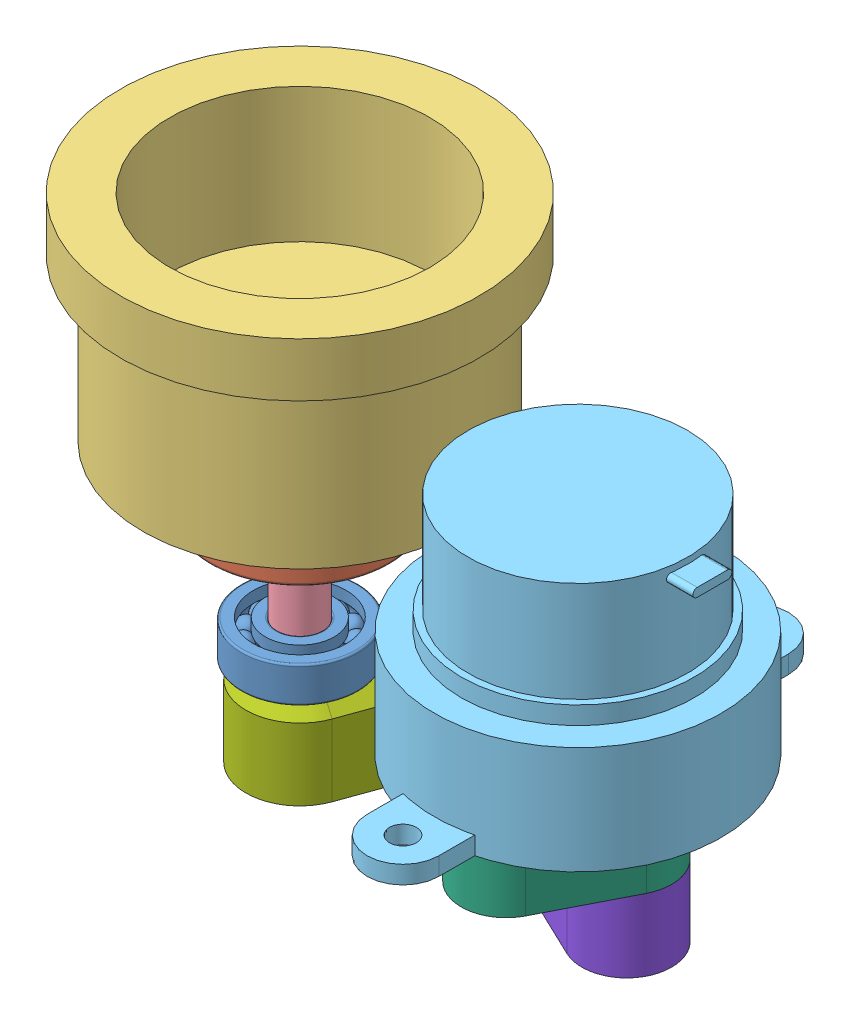
SolidWorks assembly 摇头底座装配体, configuration Default. Lengths in mm.
Overall size (74.74 63 55.47).
14 component instances, 12 part files, 33 mates.
Components (placement in the parent):
- 风扇底座外壳-1: 风扇底座外壳 [默认] at origin size (80 55 60) (hidden)
- Rolling bearings 619-5 GB 276-94-1: Rolling bearings 619-5 GB 276-94 [Rolling bearings 619-5 GB 276-94] at (0 22 0) x (0 1 0) z (-0.041534 0 0.999137) size (4 13 13)
- Rolling bearings 619-9 GB 276-94-1: Rolling bearings 619-9 GB 276-94 [Rolling bearings 619-9 GB 276-94] at (0 37 0) x (0 1 0) z (0.719572 0 0.694418) size (6 20 20)
- 风扇摇头底座-1: 风扇摇头底座 [默认] at (0 34 0) x (0.55495 0 0.831883) z (-0.831883 0 0.55495) size (40 31 40)
- M4轴肩螺丝绘制-1: M4轴肩螺丝绘制 [默认] at (0 8 0) x (0.067555 0 -0.997716) z (0 1 0) size (9 9 41.5)
- 小电动机-1: 小电动机 [默认] at (31 26.2 0) x (-1 0 0) z (0 0 -1) size (32 35.4 47)
- 曲柄-1: 曲柄 [默认] at (23 10 0) x (0.45445 0 -0.890772) z (0.890772 0 0.45445) size (20 10 10)
- 摇杆-1: 摇杆 [默认] at (0 10 0) x (0.339342 0 -0.940663) z (0.940663 0 0.339342) size (32 10 12)
- 连杆-1: 连杆 [默认] at (6.7868 2 -18.8133) x (0.902507 0 0.430676) z (-0.430676 0 0.902507) size (33 8 10)
- M3轴肩螺丝绘制-1: M3轴肩螺丝绘制 [默认] at (27.5445 21.5 -8.9077) x (-0.278627 0 -0.960399) z (0 -1 0) size (7 7 19.5)
- M3轴肩螺丝绘制-2: M3轴肩螺丝绘制 [默认] at (6.7868 21.5 -18.8133) x (-0.865706 0 -0.500553) z (0 -1 0) size (7 7 19.5)
- M3防松螺母-1: M3防松螺母 [默认] at (27.5445 15.5 -8.9077) x (-0.17481 0 0.984602) z (-0.984602 0 -0.17481) size (5.5 3.9 6.29)
- M3防松螺母-2: M3防松螺母 [默认] at (6.7868 15.5 -18.8133) x (0.176453 0 0.984309) z (-0.984309 0 0.176453) size (5.5 3.9 6.29)
- M4防松螺母-1: M4防松螺母 [默认] at (0 15 0) x (0.176453 0 0.984309) z (0.984309 0 -0.176453) size (7 5 8.02)
Mates (geometry in assembly coordinates):
- 同心1: concentric anti-aligned: cylinder of 风扇底座外壳-1 through (0 40 0) axis (0 1 0) radius 6.5; cylinder of Rolling bearings 619-5 GB 276-94-1 through (0 13.2893 0) axis (0 -1 0) radius 6.5
- 重合1: coincident anti-aligned: plane of 风扇底座外壳-1 through (-6.5 24 0) normal (0 -1 0); plane of Rolling bearings 619-5 GB 276-94-1 through (-6.4944 24 -0.27) normal (0 1 0)
- 同心2: concentric anti-aligned: cylinder of 风扇底座外壳-1 through (0 40 0) axis (0 1 0) radius 10; cylinder of Rolling bearings 619-9 GB 276-94-1 through (0 28.2893 0) axis (0 -1 0) radius 10
- 重合2: coincident anti-aligned: plane of 风扇底座外壳-1 through (-8 34 0) normal (0 1 0); plane of Rolling bearings 619-9 GB 276-94-1 through (-6.9442 34 7.1957) normal (0 -1 0)
- 同心3: concentric anti-aligned: cylinder of 风扇底座外壳-1 through (0 0 0) axis (0 1 0) radius 18; cylinder of 风扇摇头底座-1 through (0 34 0) axis (0 -1 0) radius 14.5
- 重合3: coincident anti-aligned: plane of Rolling bearings 619-9 GB 276-94-1 through (-3.1249 40 3.2381) normal (0 1 0); plane of 风扇摇头底座-1 through (-2.4973 40 -3.7435) normal (0 -1 0)
- 同心5: concentric aligned: cylinder of 风扇摇头底座-1 through (0 34 0) axis (0 -1 0) radius 4.75; cylinder of M4轴肩螺丝绘制-1 through (0 8 0) axis (0 -1 0) radius 2.5
- 重合4: coincident anti-aligned: plane of 风扇摇头底座-1 through (-2.636 46 -3.9514) normal (0 1 0); plane of M4轴肩螺丝绘制-1 through (-2.4943 46 -0.1689) normal (0 -1 0)
- 平行1: parallel anti-aligned: plane of 小电动机-1 through (31 26.2 0) normal (-1 0 0)
- 平行2: parallel aligned: plane of 小电动机-1 through (31 26.2 0) normal (0 1 0)
- 平行3: parallel anti-aligned: plane of 小电动机-1 through (31 26.2 0) normal (0 0 -1)
- 重合5: coincident anti-aligned: plane of 小电动机-1 through (31 26.2 0) normal (0 0 -1)
- 同心6: concentric aligned: cylinder of 小电动机-1 through (23 26.2 0) axis (0 1 0) radius 2.5; cylinder of 曲柄-1 through (23 16 0) axis (0 1 0) radius 2.5
- 重合6: coincident anti-aligned: plane of 小电动机-1 through (23 16 0) normal (0 -1 0); plane of 曲柄-1 through (23 16 0) normal (0 1 0)
- 同心7: concentric anti-aligned: cylinder of 风扇底座外壳-1 through (0 40 0) axis (0 1 0) radius 4.5; cylinder of 摇杆-1 through (0 10 0) axis (0 -1 0) radius 2.55
- 重合7: coincident anti-aligned: plane of Rolling bearings 619-5 GB 276-94-1 through (-6.4944 20 -0.27) normal (0 -1 0); plane of 摇杆-1 through (0 20 0) normal (0 1 0)
- 距离1: distance = 31 mm anti-aligned: plane of 小电动机-1 through (31 26.2 0) normal (-1 0 0)
- 距离3: distance = 1.6 mm anti-aligned: plane of 小电动机-1 through (43.25 51.4 0) normal (0 1 0); plane of 风扇底座外壳-1 through (0 53 0) normal (0 -1 0)
- 同心8: concentric aligned: cylinder of 摇杆-1 through (6.7868 20 -18.8133) axis (0 -1 0) radius 6; cylinder of 连杆-1 through (6.7868 10 -18.8133) axis (0 -1 0) radius 5
- 同心9: concentric aligned: cylinder of 曲柄-1 through (27.5445 20 -8.9077) axis (0 -1 0) radius 5; cylinder of 连杆-1 through (27.5445 10 -8.9077) axis (0 -1 0) radius 5
- 重合9: coincident anti-aligned: plane of 摇杆-1 through (0 10 0) normal (0 -1 0); plane of 连杆-1 through (6.7868 10 -18.8133) normal (0 1 0)
- 同心10: concentric anti-aligned: cylinder of 连杆-1 through (27.5445 2 -8.9077) axis (0 -1 0) radius 3.75; cylinder of M3轴肩螺丝绘制-1 through (27.5445 21.5 -8.9077) axis (0 1 0) radius 2
- 重合10: coincident anti-aligned: plane of 连杆-1 through (25.6718 5.5 -9.8014) normal (0 -1 0); plane of M3轴肩螺丝绘制-1 through (29.4653 5.5 -9.465) normal (0 1 0)
- 同心11: concentric anti-aligned: cylinder of 连杆-1 through (6.7868 2 -18.8133) axis (0 -1 0) radius 3.75; cylinder of M3轴肩螺丝绘制-2 through (6.7868 21.5 -18.8133) axis (0 1 0) radius 2
- 重合11: coincident anti-aligned: plane of 连杆-1 through (4.9141 5.5 -19.7069) normal (0 -1 0); plane of M3轴肩螺丝绘制-2 through (7.7879 5.5 -20.5447) normal (0 1 0)
- 同心12: concentric anti-aligned: cylinder of M3轴肩螺丝绘制-1 through (27.5445 21.5 -8.9077) axis (0 1 0) radius 1.5; cylinder of M3防松螺母-1 through (27.5445 15.5 -8.9077) axis (0 -1 0) radius 1.25
- 重合12: coincident anti-aligned: plane of M3轴肩螺丝绘制-1 through (28.9851 15.5 -9.3257) normal (0 1 0); plane of M3防松螺母-1 through (27.5445 15.5 -8.9077) normal (0 -1 0)
- 同心13: concentric anti-aligned: cylinder of M3轴肩螺丝绘制-2 through (6.7868 21.5 -18.8133) axis (0 1 0) radius 1.5; cylinder of M3防松螺母-2 through (6.7868 15.5 -18.8133) axis (0 -1 0) radius 1.25
- 重合13: coincident anti-aligned: plane of M3轴肩螺丝绘制-2 through (7.5377 15.5 -20.1118) normal (0 1 0); plane of M3防松螺母-2 through (6.7868 15.5 -18.8133) normal (0 -1 0)
- 平行4: parallel aligned: plane of 摇杆-1 through (-5.644 20 -2.0361) normal (-0.940663 0 -0.339342); plane of M3防松螺母-2 through (4.7388 17.9 -21.24) normal (-0.940663 0 -0.339342)
- 同心14: concentric anti-aligned: cylinder of M4轴肩螺丝绘制-1 through (0 8 0) axis (0 -1 0) radius 2; cylinder of M4防松螺母-1 through (0 15 0) axis (0 1 0) radius 1.65
- 平行5: parallel aligned: plane of 摇杆-1 through (-5.644 20 -2.0361) normal (-0.940663 0 -0.339342); plane of M4防松螺母-1 through (-3.978 12.1 0.7131) normal (-0.940663 0 -0.339342)
- 重合14: coincident aligned: plane of 摇杆-1 through (0 10 0) normal (0 -1 0); plane of M4防松螺母-1 through (0 10 0) normal (0 -1 0)
